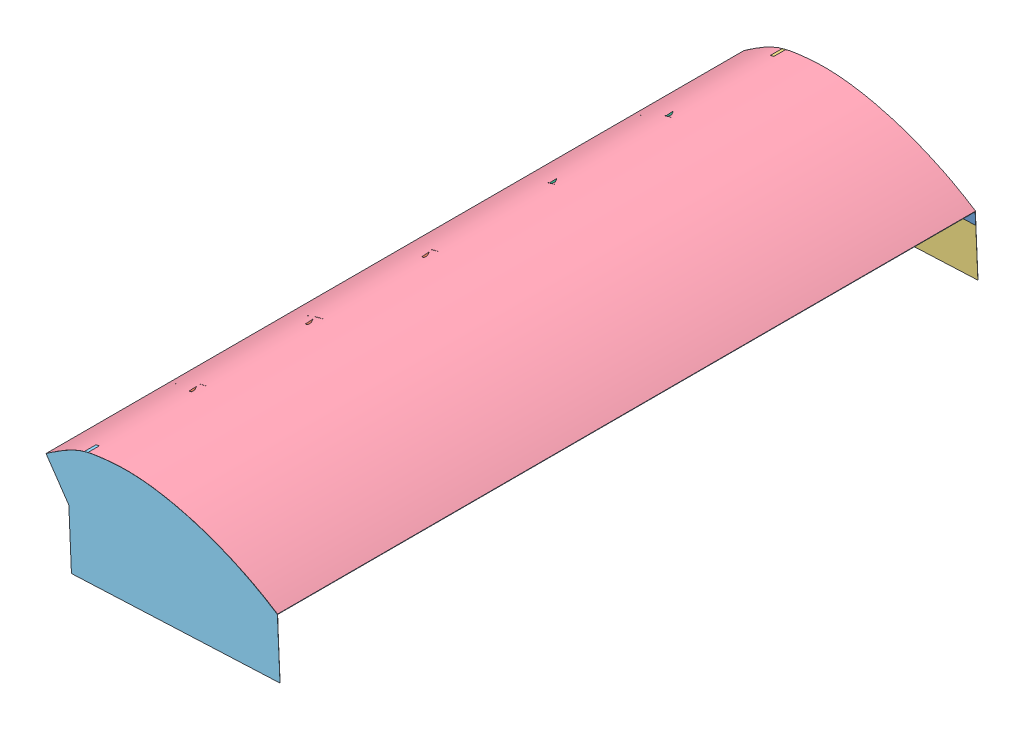
SolidWorks assembly Assem1, configuration Default. Lengths in mm.
Overall size (1574.66 883.46 600.2).
9 component instances, 6 part files, 25 mates.
Components (placement in the parent):
- bottom-1: bottom [Default] at (1835.1696 -274.3274 185.0351) size (1554.97 883.46 600)
- compartement-1: compartement [Default] at (1835.1696 -274.3274 684.9351) size (198.96 53.89 10.11)
- sideb-1: sideb [Default] at (1835.1696 -274.3274 184.9351) size (201.21 103.84 10.1)
- top-1: top [Default] at (1836.403 -270.9438 184.9351) x (0.999998 0.001987 0) z (0 0 1) size (199.07 45.8 600.2)
- side-2: side [Default] at (1835.1696 -274.3274 785.0351) size (201.21 103.84 10)
- compartement-2: compartement [Default] at (1835.1696 -274.3274 584.9351) size (198.96 53.89 10.11)
- compartement-3: compartement [Default] at (1835.1696 -274.3274 484.9351) size (198.96 53.89 10.11)
- compartement_L-1: compartement_L [Default] at (1835.1696 -274.3274 385.1351) size (198.96 53.89 10.11)
- compartement_L-2: compartement_L [Default] at (1835.1696 -274.3274 285.1351) size (198.96 53.89 10.11)
Mates (geometry in assembly coordinates):
- Coincident1: coincident anti-aligned: plane of bottom-1 through (1835.1696 -274.3274 185.0351) normal (0 0 -1); plane of sideb-1 through (175.634 340.9157 185.0351) normal (0 0 1)
- Coincident4: coincident anti-aligned: plane of bottom-1 through (1835.1696 -274.3274 785.0351) normal (0 0 1); plane of side-2 through (175.634 340.9157 785.0351) normal (0 0 -1)
- Coincident5: coincident anti-aligned: plane of bottom-1 through (111.194 291.0268 785.0351) normal (-0.045052 0.998985 0); plane of compartement-1 through (111.194 291.0268 685.0351) normal (0.045052 -0.998985 0)
- Coincident7: coincident aligned: line of side-2 through (111.194 291.0268 785.1351) axis (0 0 -1); line of compartement-1 through (111.194 291.0268 685.0351) axis (0 0 -1)
- Coincident8: coincident aligned: plane of top-1 through (175.6483 341.0005 785.1351) normal (0 0 1); plane of side-2 through (175.634 340.9157 785.1351) normal (0 0 1)
- Coincident9: coincident: plane of bottom-1 through (111.194 291.0268 785.0351) normal (-0.045052 0.998985 0); plane of ? through (111.194 291.0268 600.8761) normal (0.045052 -0.998985 0)
- Coincident10: coincident anti-aligned: plane of bottom-1 through (111.194 291.0268 785.0351) normal (-0.045052 0.998985 0); plane of compartement-2 through (111.194 291.0268 585.0351) normal (0.045052 -0.998985 0)
- Coincident11: coincident anti-aligned: plane of bottom-1 through (111.194 291.0268 785.0351) normal (-0.045052 0.998985 0); plane of compartement-3 through (111.194 291.0268 485.0351) normal (0.045052 -0.998985 0)
- Coincident12: coincident anti-aligned: plane of bottom-1 through (111.194 291.0268 785.0351) normal (-0.045052 0.998985 0); plane of compartement_L-1 through (111.194 291.0268 385.0351) normal (0.045052 -0.998985 0)
- Coincident13: coincident anti-aligned: plane of bottom-1 through (111.194 291.0268 785.0351) normal (-0.045052 0.998985 0); plane of compartement_L-2 through (111.194 291.0268 285.0351) normal (0.045052 -0.998985 0)
- Coincident14: coincident: plane of bottom-1 through (111.194 291.0268 785.0351) normal (-0.045052 0.998985 0); plane of ? through (111.194 291.0268 218.1645) normal (0.045052 -0.998985 0)
- Coincident15: coincident anti-aligned: line of bottom-1 through (111.194 291.0268 785.0351) axis (0 0 -1); line of compartement_L-1 through (111.194 291.0268 375.0351) axis (0 0 1)
- Coincident16: coincident aligned: line of bottom-1 through (111.194 291.0268 784.9351) axis (0 0 -1); line of ? through (111.194 291.0268 610.8761) axis (0 0 -1)
- Coincident17: coincident aligned: line of bottom-1 through (111.194 291.0268 785.0351) axis (0 0 -1); line of compartement-2 through (111.194 291.0268 595.0351) axis (0 0 -1)
- Coincident18: coincident aligned: line of bottom-1 through (111.194 291.0268 785.0351) axis (0 0 -1); line of compartement-3 through (111.194 291.0268 495.0351) axis (0 0 -1)
- Coincident19: coincident anti-aligned: line of bottom-1 through (111.194 291.0268 785.0351) axis (0 0 -1); line of compartement_L-2 through (111.194 291.0268 275.0351) axis (0 0 1)
- Coincident20: coincident anti-aligned: line of bottom-1 through (111.194 291.0268 784.9351) axis (0 0 -1); line of ? through (111.194 291.0268 208.1645) axis (0 0 1)
- Distance2: distance = 100 mm anti-aligned: plane of sideb-1 through (175.634 340.9157 185.0351) normal (0 0 1); plane of compartement_L-2 through (175.634 340.9157 285.0351) normal (0 0 -1)
- Distance3: distance = 200 mm anti-aligned: plane of compartement_L-1 through (175.634 340.9157 385.0351) normal (0 0 -1); plane of sideb-1 through (175.634 340.9157 185.0351) normal (0 0 1)
- Distance5: distance = 200 mm anti-aligned: plane of compartement-2 through (175.634 340.9157 585.0351) normal (0 0 1); plane of side-2 through (175.634 340.9157 785.0351) normal (0 0 -1)
- Distance6: distance = 300 mm anti-aligned: plane of compartement-3 through (175.634 340.9157 485.0351) normal (0 0 1); plane of side-2 through (175.634 340.9157 785.0351) normal (0 0 -1)
- Distance7: distance = 100 mm anti-aligned: plane of compartement-1 through (175.634 340.9157 685.0351) normal (0 0 1); plane of side-2 through (175.634 340.9157 785.0351) normal (0 0 -1)
- Lock1: lock: unknown of bottom-1; unknown of side-2
- Lock2: lock: unknown of bottom-1; unknown of sideb-1
- Coincident28: coincident aligned: line of top-1 through (91.6186 319.4209 785.1351) axis (0 0 -1); line of compartement-3 through (91.6186 319.4209 495.0351) axis (0 0 -1)
